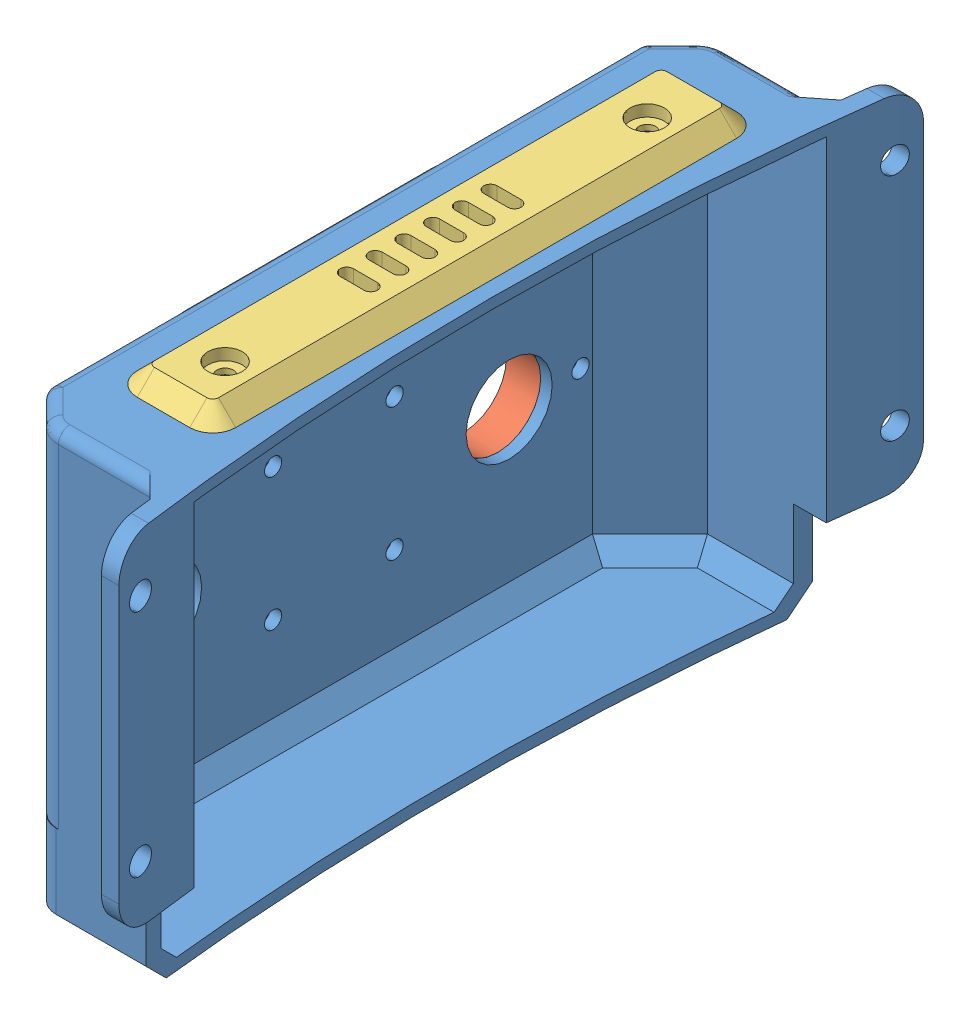
SolidWorks assembly 摄像头装配V2, configuration 默认. Lengths in mm.
Overall size (40.94 80 140).
4 component instances, 4 part files, 4 mates.
Components (placement in the parent):
- 摄像头保护罩V2-1: 摄像头保护罩V2 [默认] at (19.9963 -26.6393 149.0098) size (34.94 77 140)
- 摄像头盖板-1: 摄像头盖板 [默认] at (-36.6074 9.1364 139.8571) x (0 -1 0) z (0 0 1) size (28.93 6 92.69)
- 顶部装饰板-1: 顶部装饰板 [默认] at (-12.243 33.3607 138.4338) x (0 0 -1) z (1 0 0) size (95.16 3 17.14)
- 超声波保护盖-1: 超声波保护盖 [默认] at (-30.6074 17.323 139.3657) x (0 0 -1) z (0 1 0) size (61.81 4.89 22.11)
Mates (geometry in assembly coordinates):
- 重合1: coincident anti-aligned: plane of 摄像头保护罩V2-1 through (-30.6074 33.3607 149.0098) normal (-1 0 0); plane of 摄像头盖板-1 through (-30.6074 -10.7103 106.6569) normal (1 0 0)
- 重合2: coincident anti-aligned: plane of 摄像头保护罩V2-1 through (19.9963 33.3607 149.0098) normal (0 1 0); plane of 顶部装饰板-1 through (-7.6734 33.3607 94.8539) normal (0 -1 0)
- 重合5: coincident anti-aligned: plane of 摄像头保护罩V2-1 through (-30.6074 33.3607 149.0098) normal (-1 0 0); plane of 超声波保护盖-1 through (-30.6074 16.3808 120.1511) normal (1 0 0)
- 平行2: parallel anti-aligned: plane of 顶部装饰板-1 through (-7.6734 36.3607 94.8539) normal (0 1 0); plane of 超声波保护盖-1 through (-34.6074 5.3254 120.1511) normal (0 -1 0)
